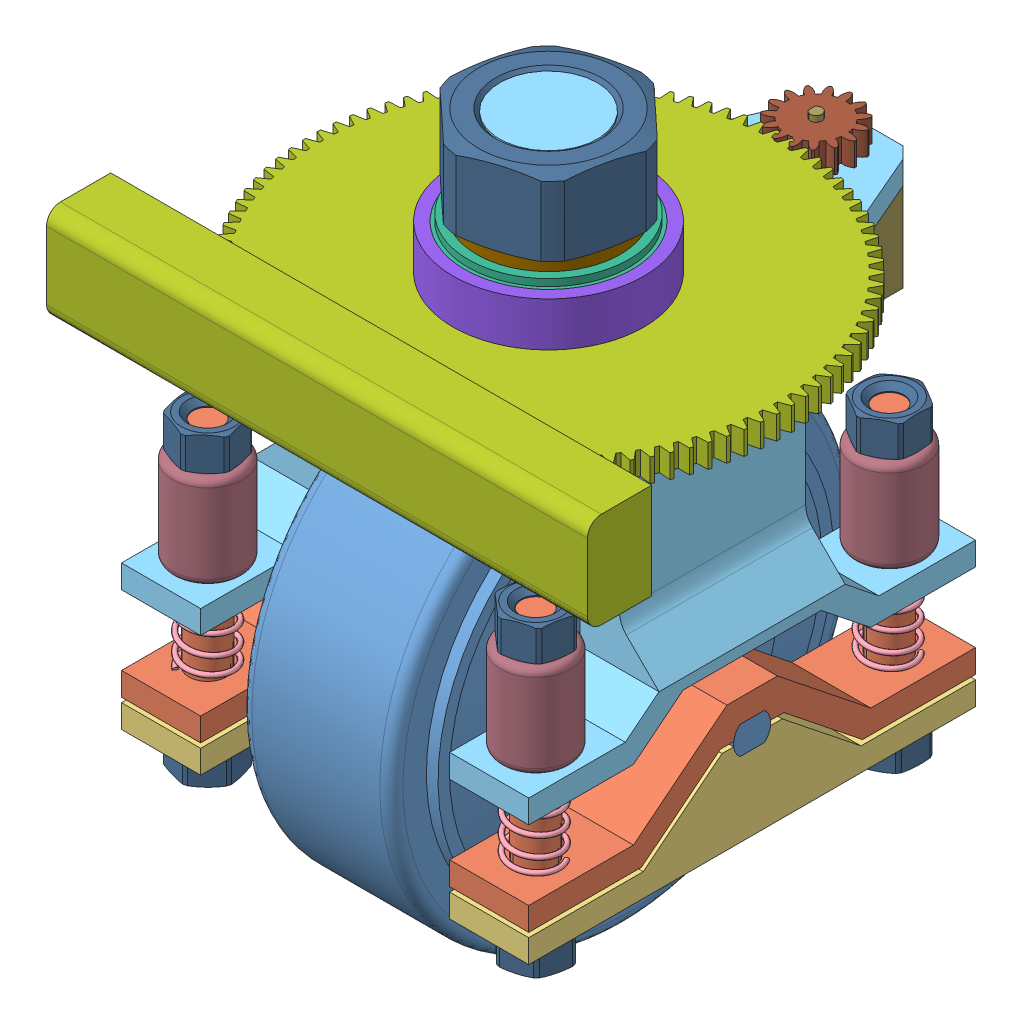
SolidWorks assembly ТП.SH21(K3).01.00 - Привод поворотный (мод 2), configuration 00. Lengths in mm.
Overall size (232.47 289 236.15).
30 component instances, 13 part files, 50 mates.
Components (placement in the parent):
- Мотор-колесо ZLLG80ASM800-1: Мотор-колесо ZLLG80ASM800 [По умолчанию] x (1 0 0) z (0 1 0) size (175 200 200)
- ТП.SH21(K2).02.03 - Верхний кронштейн К2-1: ТП.SH21(K2).02.03 - Верхний кронштейн К2 [--] at (-53.5 0 0) x (0 0 -1) z (1 0 0) size (192 129 34)
- ТП.SH21(K2).04 - Прижим К2-1: ТП.SH21(K2).04 - Прижим К2 [--] at (-53.5 0 0) x (0 0 -1) z (1 0 0) size (192 37 34)
- ТП.SH21(K3).01.01 - Пружина 14х30-1: ТП.SH21(K3).01.01 - Пружина 14х30 [--] at (-70.5 -16 -76) size (22.41 30 22.54)
- ТП.SH21(K3).01.02 - Кулак-1: ТП.SH21(K3).01.02 - Кулак [--] at (-87.5 14 0) x (0 0 -1) z (1 0 0) size (232.15 174 175)
- Подшипник 2007910А (72х50х15)-1: Подшипник 2007910А (72х50х15) [--] at (0 130 0) x (0 -1 0) z (0 0 1) size (15 72 72)
- Подшипник 2007910А (72х50х15)-3: Подшипник 2007910А (72х50х15) [--] at (0 135 0) x (0 1 0) z (0.408326 0 -0.912836) size (15 72 72)
- ТП.SH21(K3).01.03 - Половинная звезда z100(2)-2: ТП.SH21(K3).01.03 - Половинная звезда z100(2) [DIN - Spur gear 2M 100T 20PA 10FW ---S100A75H50L0.2N] at (0 128 0) x (0 -1 0) z (0 0 1) size (41.2 232.47 201.57)
- ТП.SH21(K3).01.04 - Обойма ступицы-1: ТП.SH21(K3).01.04 - Обойма ступицы [--] at (0 115 0) size (82 29 82)
- ТП.SH21(K2).05 - Кольцо ступицы-1: ТП.SH21(K2).05 - Кольцо ступицы [--] at (0 155 0) x (-0.827904 0 -0.56087) z (0.56087 0 -0.827904) size (61.75 5 61.75)
- Гайка (ГОСТ ISO 4032-2014)-1: Гайка (ГОСТ ISO 4032-2014) [Гайка М42 (ГОСТ ISO 4032)] at (0 172 0) x (-0.974958 0 -0.222391) z (0 -1 0) size (65 71.3 34)
- ТП.SH21(K2).03 - Шестерня малая-1: ТП.SH21(K2).03 - Шестерня малая [DIN - Spur gear 2M 15T 20PA 10FW ---S15B15H23L5N] at (0 118 -115) x (0 1 0) z (0 0 1) size (23 33.72 33.9)
- 17HS4401 (Nema17)-1: 17HS4401 (Nema17) [--] at (0 105 -115) x (0 0 -1) z (0 1 0) size (42.3 42.3 63.5)
- Линейный подшипник (16х30х40)-1: Линейный подшипник (16х30х40) [--] at (-70.5 44 -76) x (-0.878925 0 0.476961) z (0 -1 0) size (30 30 40)
- Гайка (ГОСТ ISO 4032-2014)-2: Гайка (ГОСТ ISO 4032-2014) [Гайка М16 (ГОСТ ISO 4032)] at (-70.5 71.4 -76) x (1 0 0) z (0 -1 0) size (24 26.75 14.8)
- Гайка (ГОСТ ISO 4032-2014)-3: Гайка (ГОСТ ISO 4032-2014) [Гайка М16 (ГОСТ ISO 4032)] at (-70.5 -45.4 -76) x (-0.546944 0 -0.837169) z (0 1 0) size (24 26.75 14.8)
- Гайка (ГОСТ ISO 4032-2014)-5: Гайка (ГОСТ ISO 4032-2014) [Гайка М16 (ГОСТ ISO 4032)] at (-70.5 71.4 76) x (0.982082 0 -0.188455) z (0 -1 0) size (24 26.75 14.8)
- Линейный подшипник (16х30х40)-2: Линейный подшипник (16х30х40) [--] at (-70.5 44 76) x (-0.77329 0 0.634052) z (0 -1 0) size (30 30 40)
- ТП.SH21(K3).01.01 - Пружина 14х30-2: ТП.SH21(K3).01.01 - Пружина 14х30 [--] at (-70.5 -16 76) x (0.982082 0 -0.188455) z (0.188455 0 0.982082) size (22.41 30 22.54)
- Гайка (ГОСТ ISO 4032-2014)-6: Гайка (ГОСТ ISO 4032-2014) [Гайка М16 (ГОСТ ISO 4032)] at (-70.5 -45.4 76) x (-0.694913 0 -0.719094) z (0 1 0) size (24 26.75 14.8)
- ТП.SH21(K2).04 - Прижим К2-2: ТП.SH21(K2).04 - Прижим К2 [--] at (87.5 0 0) x (0 0 -1) z (1 0 0) size (192 37 34)
- ТП.SH21(K2).02.03 - Верхний кронштейн К2-2: ТП.SH21(K2).02.03 - Верхний кронштейн К2 [--] at (87.5 0 0) x (0 0 -1) z (1 0 0) size (192 129 34)
- ТП.SH21(K3).01.01 - Пружина 14х30-4: ТП.SH21(K3).01.01 - Пружина 14х30 [--] at (70.3984 -16 76.5294) x (-0.982082 0 -0.188455) z (0.188455 0 -0.982082) size (22.41 30 22.54)
- ТП.SH21(K3).01.01 - Пружина 14х30-5: ТП.SH21(K3).01.01 - Пружина 14х30 [--] at (70.5 -16 -75.4609) x (-1 0 0) z (0 0 -1) size (22.41 30 22.54)
- Линейный подшипник (16х30х40)-4: Линейный подшипник (16х30х40) [--] at (70.5 44 -76) x (0.878925 0 0.476961) z (0 1 0) size (30 30 40)
- Линейный подшипник (16х30х40)-5: Линейный подшипник (16х30х40) [--] at (70.5 44 76) x (0.77329 0 0.634052) z (0 1 0) size (30 30 40)
- Гайка (ГОСТ ISO 4032-2014)-9: Гайка (ГОСТ ISO 4032-2014) [Гайка М16 (ГОСТ ISO 4032)] at (70.5 71.4 76) x (-0.982082 0 -0.188455) z (0 1 0) size (24 26.75 14.8)
- Гайка (ГОСТ ISO 4032-2014)-10: Гайка (ГОСТ ISO 4032-2014) [Гайка М16 (ГОСТ ISO 4032)] at (70.5 71.4 -76) x (-1 0 0) z (0 1 0) size (24 26.75 14.8)
- Гайка (ГОСТ ISO 4032-2014)-11: Гайка (ГОСТ ISO 4032-2014) [Гайка М16 (ГОСТ ISO 4032)] at (70.5 -45.4 -76) x (0.546944 0 -0.837169) z (0 -1 0) size (24 26.75 14.8)
- Гайка (ГОСТ ISO 4032-2014)-12: Гайка (ГОСТ ISO 4032-2014) [Гайка М16 (ГОСТ ISO 4032)] at (70.5 -45.4 76) x (0.694913 0 -0.719094) z (0 -1 0) size (24 26.75 14.8)
Mates (geometry in assembly coordinates):
- Совпадение1: coincident: plane of Мотор-колесо ZLLG80ASM800-1 through (0 0 0) normal (0 0 -1); plane of assembly through (0 0 0) normal (0 0 1)
- Совпадение2: coincident: plane of Мотор-колесо ZLLG80ASM800-1 through (0 0 0) normal (0 1 0); plane of assembly through (0 0 0) normal (0 1 0)
- Совпадение3: coincident: plane of Мотор-колесо ZLLG80ASM800-1 through (0 0 0) normal (1 0 0); plane of assembly through (0 0 0) normal (1 0 0)
- Совпадение4: coincident: plane of Мотор-колесо ZLLG80ASM800-1 through (-53.5 0 0) normal (-1 0 0); plane of ТП.SH21(K2).02.03 - Верхний кронштейн К2-1 through (-53.5 0 0) normal (1 0 0)
- Концентричный1: concentric: cylinder of Мотор-колесо ZLLG80ASM800-1 through (-1100.9037 0 0) axis (-1 0 0) radius 8; cylinder of ТП.SH21(K2).02.03 - Верхний кронштейн К2-1 through (-192.2855 0 0) axis (1 0 0) radius 8
- Совпадение5: coincident: plane of Мотор-колесо ZLLG80ASM800-1 through (-87.5 6 291587.9) normal (0 1 0); plane of ТП.SH21(K2).02.03 - Верхний кронштейн К2-1 through (-192.2855 6 5.2915) normal (0 -1 0)
- Совпадение6: coincident: plane of ТП.SH21(K2).02.03 - Верхний кронштейн К2-1 through (-87.5 0 -8) normal (-1 0 0); plane of ТП.SH21(K2).04 - Прижим К2-1 through (-87.5 0 -8) normal (-1 0 0)
- Концентричный2: concentric: cylinder of Мотор-колесо ZLLG80ASM800-1 through (-1100.9037 0 0) axis (-1 0 0) radius 8; cylinder of ТП.SH21(K2).04 - Прижим К2-1 through (-192.2855 0 0) axis (1 0 0) radius 8
- Концентричный3: concentric: cylinder of ТП.SH21(K2).02.03 - Верхний кронштейн К2-1 through (-70.5 118.6274 -76) axis (0 -1 0) radius 8; cylinder of ТП.SH21(K2).04 - Прижим К2-1 through (-70.5 -3.9584 -76) axis (0 -1 0) radius 8.5
- Концентричный4: concentric: cylinder of ТП.SH21(K2).02.03 - Верхний кронштейн К2-1 through (-70.5 118.6274 -76) axis (0 -1 0) radius 8; circle of ТП.SH21(K3).01.01 - Пружина 14х30-1
- Совпадение7: coincident: plane of ТП.SH21(K2).02.03 - Верхний кронштейн К2-1 through (-192.2855 -16 -51) normal (0 1 0); circle of ТП.SH21(K3).01.01 - Пружина 14х30-1
- Совпадение8: coincident: plane of ТП.SH21(K2).02.03 - Верхний кронштейн К2-1 through (-87.5 0 -8) normal (-1 0 0); plane of ТП.SH21(K3).01.02 - Кулак-1 through (-87.5 14 0) normal (1 0 0)
- Совпадение9: coincident: plane of ТП.SH21(K3).01.01 - Пружина 14х30-1 through (-81.5 14 -61) normal (0 1 0); plane of ТП.SH21(K3).01.02 - Кулак-1 through (-87.5 14 0) normal (0 1 0)
- Совпадение10: coincident: plane of ТП.SH21(K3).01.02 - Кулак-1 through (-87.5 14 0) normal (0 0 -1); plane of assembly through (0 0 0) normal (0 0 1)
- Совпадение11: coincident: plane of ТП.SH21(K3).01.02 - Кулак-1 through (85.8449 115 0) normal (0 1 0); plane of Подшипник 2007910А (72х50х15)-1 through (34.561 115 0) normal (0 -1 0)
- Расстояние1: distance = 5 mm: plane of Подшипник 2007910А (72х50х15)-3 through (32.3144 135 14.4547) normal (0 -1 0); plane of Подшипник 2007910А (72х50х15)-1 through (35.4 130 0) normal (0 1 0)
- Концентричный6: concentric: cylinder of Подшипник 2007910А (72х50х15)-1 through (0 1130 0) axis (0 1 0) radius 25; cylinder of Подшипник 2007910А (72х50х15)-3 through (0 -865 0) axis (0 -1 0) radius 25
- Совпадение12: coincident: circle of Подшипник 2007910А (72х50х15)-1; plane of ТП.SH21(K3).01.03 - Половинная звезда z100(2)-2 through (0 118 0) normal (0 -1 0)
- Совпадение13: coincident: plane of ТП.SH21(K3).01.03 - Половинная звезда z100(2)-2 through (0 128 0) normal (1 0 0); plane of assembly through (0 0 0) normal (1 0 0)
- Совпадение14: coincident: plane of ТП.SH21(K3).01.03 - Половинная звезда z100(2)-2 through (0 128 0) normal (0 0 1); plane of assembly through (0 0 0) normal (0 0 1)
- Совпадение15: coincident: plane of ТП.SH21(K3).01.04 - Обойма ступицы-1 through (0 115 0) normal (0 0 1); plane of assembly through (0 0 0) normal (0 0 1)
- Совпадение16: coincident: plane of ТП.SH21(K3).01.04 - Обойма ступицы-1 through (0 115 0) normal (1 0 0); plane of assembly through (0 0 0) normal (1 0 0)
- Совпадение17: coincident: plane of Подшипник 2007910А (72х50х15)-1 through (34.561 115 0) normal (0 -1 0); plane of ТП.SH21(K3).01.04 - Обойма ступицы-1 through (0 115 0) normal (0 1 0)
- Совпадение18: coincident: plane of Подшипник 2007910А (72х50х15)-1 through (0 130 0) normal (0 0 1); plane of assembly through (0 0 0) normal (0 0 1)
- Совпадение19: coincident: plane of Подшипник 2007910А (72х50х15)-1 through (0 130 0) normal (1 0 0); plane of assembly through (0 0 0) normal (1 0 0)
- Совпадение20: coincident: plane of Подшипник 2007910А (72х50х15)-3 through (31.5485 150 14.1122) normal (0 1 0); plane of ТП.SH21(K2).05 - Кольцо ступицы-1 through (-16.8261 150 24.8371) normal (0 -1 0)
- Концентричный7: concentric: cylinder of ТП.SH21(K3).01.02 - Кулак-1 through (0 188 0) axis (0 -1 0) radius 21; cylinder of ТП.SH21(K2).05 - Кольцо ступицы-1 through (0 62.6751 0) axis (0 1 0) radius 21.5
- Совпадение21: coincident: plane of ТП.SH21(K2).05 - Кольцо ступицы-1 through (0 155 0) normal (0 1 0); plane of Гайка (ГОСТ ISO 4032-2014)-1 through (6.6717 155 -29.2487) normal (0 -1 0)
- Концентричный8: concentric: cylinder of ТП.SH21(K3).01.02 - Кулак-1 through (0 188 0) axis (0 -1 0) radius 21; cylinder of Гайка (ГОСТ ISO 4032-2014)-1 through (0 19.2598 0) axis (0 -1 0) radius 17.1029
- Совпадение22: coincident: plane of ТП.SH21(K3).01.03 - Половинная звезда z100(2)-2 through (0 128 0) normal (0 1 0); plane of ТП.SH21(K2).03 - Шестерня малая-1 through (0 128 -115) normal (0 1 0)
- Совпадение23: coincident: plane of ТП.SH21(K2).03 - Шестерня малая-1 through (0 118 -115) normal (-1 0 0); plane of assembly through (0 0 0) normal (1 0 0)
- Расстояние3: distance = 115 mm: cylinder of ТП.SH21(K3).01.04 - Обойма ступицы-1 through (0 -885 0) axis (0 -1 0) radius 41; cylinder of ТП.SH21(K2).03 - Шестерня малая-1 through (0 141.0001 -115) axis (0 -1 0) radius 2.5
- Концентричный9: concentric: cylinder of ТП.SH21(K2).03 - Шестерня малая-1 through (0 141.0001 -115) axis (0 -1 0) radius 2.5; cylinder of 17HS4401 (Nema17)-1 through (0 130.5 -115) axis (0 -1 0) radius 2.5
- Совпадение24: coincident: plane of ТП.SH21(K3).01.02 - Кулак-1 through (41.2311 105 0) normal (0 -1 0); plane of 17HS4401 (Nema17)-1 through (0 105 -115) normal (0 1 0)
- Параллельность1: parallel: plane of 17HS4401 (Nema17)-1 through (16.15 67 -93.85) normal (0 0 1); plane of assembly through (0 0 0) normal (0 0 1)
- Совпадение25: coincident: plane of ТП.SH21(K3).01.02 - Кулак-1 through (85.8449 24 -54.4985) normal (0 1 0); plane of Линейный подшипник (16х30х40)-1 through (-70.5 24 -76) normal (0 -1 0)
- Концентричный10: concentric: cylinder of ТП.SH21(K2).02.03 - Верхний кронштейн К2-1 through (-70.5 118.6274 -76) axis (0 -1 0) radius 8; cylinder of Линейный подшипник (16х30х40)-1 through (-70.5 24 -76) axis (0 1 0) radius 8
- Совпадение26: coincident: plane of Линейный подшипник (16х30х40)-1 through (-70.5 64 -76) normal (0 1 0); plane of Гайка (ГОСТ ISO 4032-2014)-2 through (-70.5 64 -64.75) normal (0 -1 0)
- Концентричный11: concentric: cylinder of ТП.SH21(K2).02.03 - Верхний кронштейн К2-1 through (-70.5 118.6274 -76) axis (0 -1 0) radius 8; cylinder of Гайка (ГОСТ ISO 4032-2014)-2 through (-70.5 -81.3402 -76) axis (0 -1 0) radius 6.2679
- Совпадение27: coincident: plane of ТП.SH21(K2).04 - Прижим К2-1 through (-192.2855 -38 0) normal (0 -1 0); plane of Гайка (ГОСТ ISO 4032-2014)-3 through (-79.9182 -38 -69.8469) normal (0 1 0)
- Концентричный12: concentric: cylinder of ТП.SH21(K2).02.03 - Верхний кронштейн К2-1 through (-70.5 118.6274 -76) axis (0 -1 0) radius 8; cylinder of Гайка (ГОСТ ISO 4032-2014)-3 through (-70.5 107.3402 -76) axis (0 1 0) radius 6.2679
- Совпадение28: coincident: plane of Гайка (ГОСТ ISO 4032-2014)-5 through (-68.3799 64 87.0484) normal (0 -1 0); plane of Линейный подшипник (16х30х40)-2 through (-70.5 64 76) normal (0 1 0)
- Концентричный13: concentric: cylinder of ТП.SH21(K2).02.03 - Верхний кронштейн К2-1 through (-70.5 118.6274 76) axis (0 -1 0) radius 8; circle of ТП.SH21(K3).01.01 - Пружина 14х30-2
- Совпадение29: coincident: plane of ТП.SH21(K2).02.03 - Верхний кронштейн К2-1 through (-192.2855 -16 51) normal (0 1 0); circle of ТП.SH21(K3).01.01 - Пружина 14х30-2
- Совпадение30: coincident: plane of ТП.SH21(K3).01.02 - Кулак-1 through (-87.5 14 0) normal (0 1 0); plane of ТП.SH21(K3).01.01 - Пружина 14х30-2 through (-78.476 14 92.8042) normal (0 1 0)
- Совпадение31: coincident: plane of ТП.SH21(K3).01.02 - Кулак-1 through (85.8449 24 -54.4985) normal (0 1 0); plane of Линейный подшипник (16х30х40)-2 through (-70.5 24 76) normal (0 -1 0)
- Концентричный14: concentric: cylinder of ТП.SH21(K2).02.03 - Верхний кронштейн К2-1 through (-70.5 118.6274 76) axis (0 -1 0) radius 8; cylinder of Линейный подшипник (16х30х40)-2 through (-70.5 24 76) axis (0 1 0) radius 8
- Концентричный15: concentric: cylinder of ТП.SH21(K2).02.03 - Верхний кронштейн К2-1 through (-70.5 118.6274 76) axis (0 -1 0) radius 8; cylinder of Гайка (ГОСТ ISO 4032-2014)-5 through (-70.5 -81.3402 76) axis (0 -1 0) radius 6.2679
- Совпадение32: coincident: plane of ТП.SH21(K2).04 - Прижим К2-1 through (-192.2855 -38 0) normal (0 -1 0); plane of Гайка (ГОСТ ISO 4032-2014)-6 through (-78.5898 -38 83.8178) normal (0 1 0)
- Концентричный16: concentric: cylinder of ТП.SH21(K2).02.03 - Верхний кронштейн К2-1 through (-70.5 118.6274 76) axis (0 -1 0) radius 8; cylinder of Гайка (ГОСТ ISO 4032-2014)-6 through (-70.5 107.3402 76) axis (0 1 0) radius 6.2679
